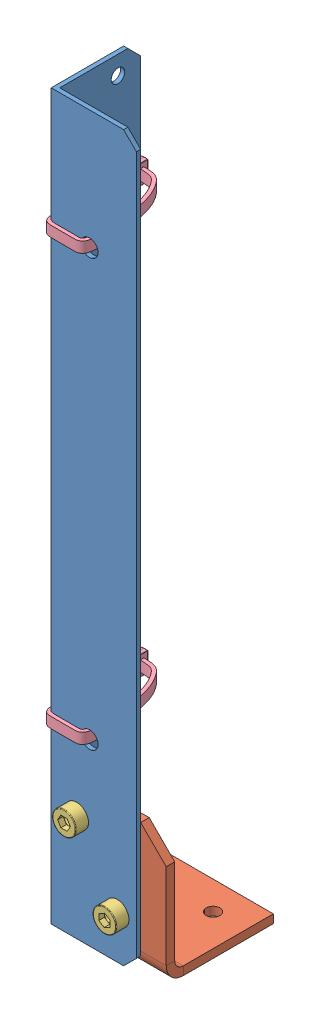
SolidWorks assembly CableChainMountFrameX, configuration Cable Chain Mount Frame X. Lengths in mm.
Overall size (60.82 192.17 76.77).
14 component instances, 9 part files, 10 mates.
Components (placement in the parent):
- Frame Base X-1: Frame Base X [axisX] at (40.3271 -13.3377 312.2808) x (1 0 0) z (0 1 0) size (20 20 170)
- FrameBaseMountBracketX-1: FrameBaseMountBracketX [Frame Base Mount Bracket X] at (41.3271 -11.3377 286.137) x (0 -1 0) z (-1 0 0) size (30.14 25.14 25)
- socket head cap screw_iso-1: socket head cap screw_iso [ISO 4762 M3 x 8 - 8N] at (46.3271 11.6623 315.2808) x (0 0 -1) z (-0.013049 0.999915 0) size (11 5.5 5.5)
- socket head cap screw_iso-2: socket head cap screw_iso [ISO 4762 M3 x 8 - 8N] at (55.8271 -3.3377 315.2808) x (0 0 -1) z (-0.463988 0.885841 0) size (11 5.5 5.5)
- cableTiePlastic-1: cableTiePlastic [Default] at (40.3322 128.512 291.8502) x (0 1 0) z (0 0 1) size (4.6 13.75 23.86)
- Cables^CableChainMountFrameX-1: Cables^CableChainMountFrameX [Default] at origin size (54.65 189.55 76.04) (hidden, virtual)
  - Copy of StepperCable^Cables_CableChainMountFrameX-1: Copy of StepperCable^Cables_CableChainMountFrameX [Default] at (0 0 -1.0135) size (54.65 183.21 57.73) (virtual)
  - Copy of Copy of StepperCable^Cables_CableChainMountFrameX-1: Copy of Copy of StepperCable^Cables_CableChainMountFrameX [Default] at (-0.3395 -8.0956 -6.2859) size (50.17 179.72 63.2) (virtual)
  - Copy of Copy of Copy of StepperCable^Cables_CableChainMountFrameX-1: Copy of Copy of Copy of StepperCable^Cables_CableChainMountFrameX [Default] at (-0.2999 -4.3903 -10.5424) size (53.22 181.73 57.42) (virtual)
  - Copy of Copy of Copy of Copy of StepperCable^Cables_CableChainMountFrameX-1: Copy of Copy of Copy of Copy of StepperCable^Cables_CableChainMountFrameX [Default] at (-1.1425 -10.8499 -10.7963) size (41.85 28.78 71.3) (virtual)
- cableTiePlastic-2: cableTiePlastic [Default] at (40.2871 28.6179 291.8086) x (0 1 0) z (0 0 1) size (4.6 13.75 23.86)
- cableTiePlastic-3: cableTiePlastic [2] at (77.2947 -7.3948 314.89) x (-0.50518 0.830059 -0.236209) z (0.602494 0.143249 -0.785163) size (5.22 21.48 12.88) (hidden)
- Nyloc nut St_Steel A2 ISO M2_5-M36-1: Nyloc nut St_Steel A2 ISO M2_5-M36 [M3 NYLOC DIN 985] at (46.3271 11.6623 309.2808) x (0.960409 0.278594 0) z (-0.278594 0.960409 0) size (6.35 4 5.5)
- Nyloc nut St_Steel A2 ISO M2_5-M36-2: Nyloc nut St_Steel A2 ISO M2_5-M36 [M3 NYLOC DIN 985] at (55.8271 -3.3377 309.2808) x (0.985781 -0.168034 0) z (0.168034 0.985781 0) size (6.35 4 5.5)
Mates (geometry in assembly coordinates):
- Coincident249: coincident anti-aligned: plane of Frame Base 2-1 through (41.3271 156.6623 311.2808) normal (1 0 0); plane of FrameBaseMountBracketX-1 through (41.3271 16.8061 311.2808) normal (-1 0 0)
- Coincident250: coincident anti-aligned: plane of Frame Base 2-1 through (60.3271 156.6623 311.2808) normal (0 0 -1); plane of FrameBaseMountBracketX-1 through (41.3271 -35.1939 311.2808) normal (0 0 1)
- Coincident257: coincident anti-aligned: plane of Frame Base 2-1 through (40.3271 156.6623 312.2808) normal (0 0 1); plane of socket head cap screw_iso-1 through (43.5773 11.6264 312.2808) normal (0 0 -1)
- Concentric145: concentric anti-aligned: cylinder of Frame Base 2-1 through (55.8271 -3.3377 311.2808) axis (0 0 -1) radius 1.6; cylinder of socket head cap screw_iso-2 through (55.8271 -3.3377 347.0308) axis (0 0 1) radius 1.5
- Coincident256: coincident anti-aligned: plane of Frame Base 2-1 through (40.3271 156.6623 312.2808) normal (0 0 1); plane of socket head cap screw_iso-2 through (53.391 -4.6137 312.2808) normal (0 0 -1)
- Coincident263: coincident anti-aligned: plane of FrameBaseMountBracketX-1 through (41.3271 -35.1939 309.2808) normal (0 0 -1); plane of Nyloc nut St_Steel A2 ISO M2_5-M36-1 through (49.3768 12.547 309.2808) normal (0 0 1)
- Concentric149: concentric anti-aligned: cylinder of socket head cap screw_iso-1 through (46.3271 11.6623 347.0308) axis (0 0 1) radius 1.5; cylinder of Nyloc nut St_Steel A2 ISO M2_5-M36-1 through (46.3271 11.6623 309.2808) axis (0 0 -1) radius 1.195
- Coincident2641: coincident anti-aligned: plane of FrameBaseMountBracketX-1 through (41.3271 -35.1939 309.2808) normal (0 0 -1); plane of Nyloc nut St_Steel A2 ISO M2_5-M36-2 through (58.9574 -3.8713 309.2808) normal (0 0 1)
- Concentric1502: concentric anti-aligned: cylinder of Frame Base 2-1 through (46.3271 11.6623 311.2808) axis (0 0 -1) radius 1.6; cylinder of socket head cap screw_iso-1 through (46.3271 11.6623 347.0308) axis (0 0 1) radius 2.75
- Coincident2642: coincident aligned: plane of Frame Base X-1 through (40.3271 -13.3377 312.2808) normal (0 -1 0); plane of FrameBaseMountBracketX-1 through (41.3271 -13.3377 286.137) normal (0 -1 0)
